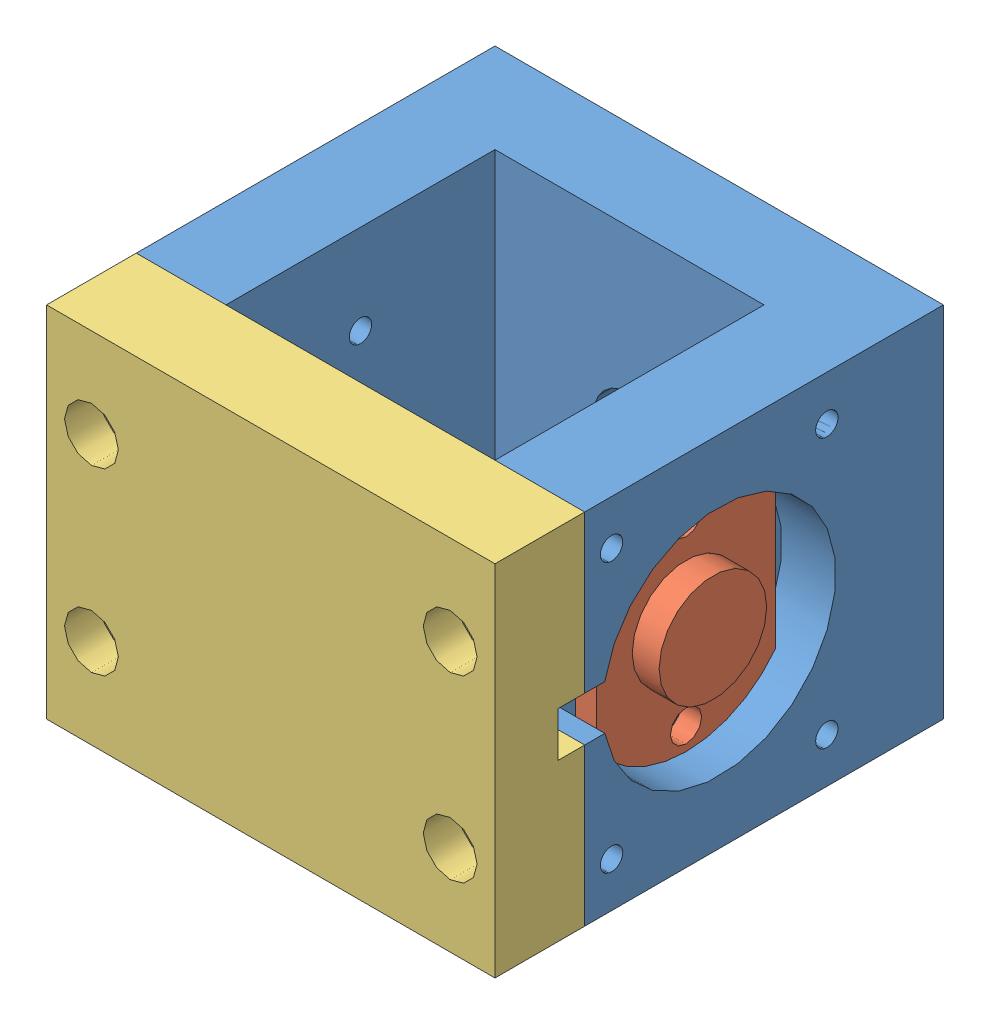
SolidWorks assembly LEDSlideAssem, configuration Default. Lengths in mm.
Overall size (50 40 50).
4 component instances, 3 part files, 9 mates.
Components (placement in the parent):
- LEDSlide-1: LEDSlide [Default] at (-0.4446 0 -1.7102) size (50 40 40)
- LED-1: LED [Default] at (18.5554 20 3.2898) x (0 -1 0) z (0 0 1) size (25 5.3 20)
- LED-2: LED [Default] at (-19.4446 20 3.2898) x (0 1 0) z (0 0 1) size (25 5.3 20)
- PowerSlide-1: PowerSlide [Default] at (0 -0.8358 0) size (50 40 10)
Mates (geometry in assembly coordinates):
- Coincident3: coincident aligned: plane of LEDSlide-1 through (-25.4446 40 18.2898) normal (-1 0 0); plane of PowerSlide-1 through (-25.4446 40 18.2898) normal (-1 0 0)
- Coincident4: coincident aligned: plane of LEDSlide-1 through (-25.4446 40 -21.7102) normal (0 1 0); plane of PowerSlide-1 through (-25.4446 40 28.2898) normal (0 1 0)
- Coincident5: coincident anti-aligned: plane of LEDSlide-1 through (24.5554 40 18.2898) normal (0 0 1); plane of PowerSlide-1 through (-25.4446 40 18.2898) normal (0 0 -1)
- Coincident6: coincident anti-aligned: plane of LEDSlide-1 through (18.5554 20 3.2898) normal (1 0 0); plane of LED-1 through (18.5554 20 3.2898) normal (-1 0 0)
- Concentric1: concentric anti-aligned: cylinder of LEDSlide-1 through (18.5554 30 3.2898) axis (1 0 0) radius 1.25; cylinder of LED-1 through (20.8554 30 3.2898) axis (-1 0 0) radius 1.75
- Concentric2: concentric anti-aligned: cylinder of LEDSlide-1 through (18.5554 10 3.2898) axis (1 0 0) radius 1.25; cylinder of LED-1 through (20.8554 10 3.2898) axis (-1 0 0) radius 1.75
- Coincident7: coincident anti-aligned: plane of LEDSlide-1 through (-19.4446 20 3.2898) normal (-1 0 0); plane of LED-2 through (-19.4446 20 3.2898) normal (1 0 0)
- Concentric3: concentric anti-aligned: cylinder of LEDSlide-1 through (-19.4446 30 3.2898) axis (-1 0 0) radius 1.25; cylinder of LED-2 through (-21.7446 30 3.2898) axis (1 0 0) radius 1.75
- Concentric4: concentric anti-aligned: cylinder of LEDSlide-1 through (-19.4446 10 3.2898) axis (-1 0 0) radius 1.25; cylinder of LED-2 through (-21.7446 10 3.2898) axis (1 0 0) radius 1.75
